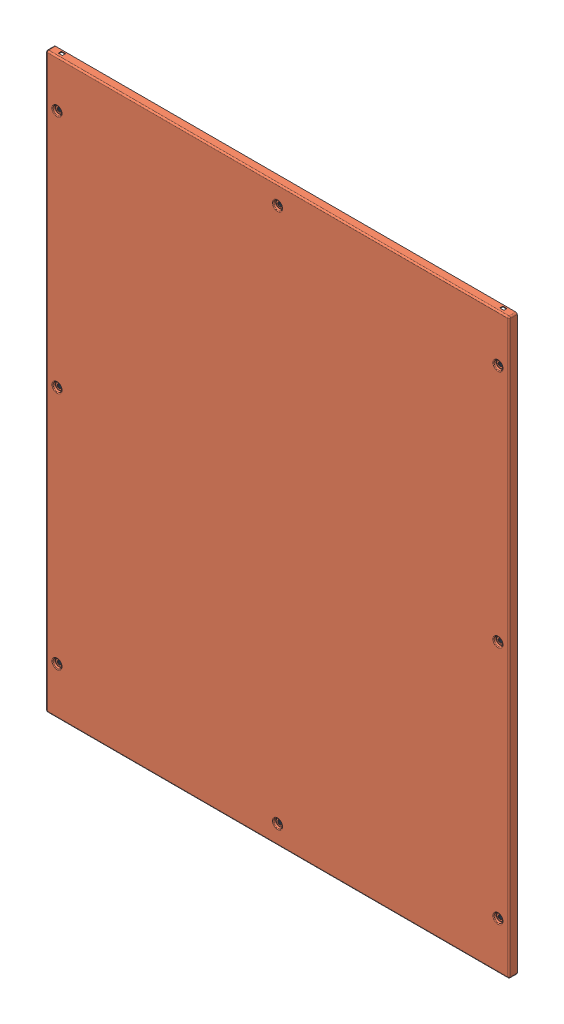
SolidWorks assembly 8176_245, configuration Default. Lengths in mm.
Overall size (968.16 1197.62 31.49).
9 component instances, 2 part files, 27 mates.
Components (placement in the parent):
- 8176_245-side-holder-1: 8176_245-side-holder [Default] at (-483.75 -39.5 -6) x (0 1 0) z (0 0 -1) size (20.59 21 24.87)
- 8176_245-side-holder-2: 8176_245-side-holder [Default] at (-483.75 -1157.5 -6) x (0 -1 0) z (0 0 -1) size (20.59 21 24.87)
- 8176_245-side-holder-3: 8176_245-side-holder [Default] at (-23.25 -1098.5 -6) x (1 0 0) z (0 0 -1) size (20.59 21 24.87)
- 8176_245-side-holder-4: 8176_245-side-holder [Default] at (-944.25 -1098.5 -6) x (-1 0 0) z (0 0 -1) size (20.59 21 24.87)
- 8176_245-side-holder-5: 8176_245-side-holder [Default] at (-23.25 -598.5 -6) x (1 0 0) z (0 0 -1) size (20.59 21 24.87)
- 8176_245-side-holder-6: 8176_245-side-holder [Default] at (-944.25 -598.5 -6) x (-1 0 0) z (0 0 -1) size (20.59 21 24.87)
- 8176_245-side-holder-7: 8176_245-side-holder [Default] at (-23.25 -98.5 -6) x (1 0 0) z (0 0 -1) size (20.59 21 24.87)
- 8176_245-side-holder-8: 8176_245-side-holder [Default] at (-944.25 -98.5 -6) x (-1 0 0) z (0 0 -1) size (20.59 21 24.87)
- 8176_245-side-1: 8176_245-side [Default] at (-483.75 -1197 0) x (-1 0 0) z (0 0 -1) size (968.16 1197.62 24.32)
Mates (geometry in assembly coordinates):
- Deckungsgleich1: coincident anti-aligned: plane of 8176_245-side-holder-3 through (-15.45 1609.6534 -6) normal (0 0 1); plane of 8176_245-side-1 through (-23.25 1612.9885 -6) normal (0 0 -1)
- Konzentrisch1: concentric aligned: cylinder of 8176_245-side-holder-3 through (-23.25 1620.1534 -12) axis (0 0 -1) radius 2.4585; cylinder of 8176_245-side-1 through (-23.25 1620.1534 -6) axis (0 0 -1) radius 4
- Deckungsgleich2: coincident anti-aligned: plane of 8176_245-side-holder-5 through (-15.45 2109.6534 -6) normal (0 0 1); plane of 8176_245-side-1 through (-23.25 2112.9885 -6) normal (0 0 -1)
- Konzentrisch2: concentric aligned: cylinder of 8176_245-side-holder-5 through (-23.25 2120.1534 -12) axis (0 0 -1) radius 2.4585; cylinder of 8176_245-side-1 through (-23.25 2120.1534 -6) axis (0 0 -1) radius 4
- Deckungsgleich3: coincident anti-aligned: plane of 8176_245-side-holder-7 through (-15.45 2609.6534 -6) normal (0 0 1); plane of 8176_245-side-1 through (-23.25 2612.9885 -6) normal (0 0 -1)
- Konzentrisch3: concentric aligned: cylinder of 8176_245-side-holder-7 through (-23.25 2620.1534 -12) axis (0 0 -1) radius 2.4585; cylinder of 8176_245-side-1 through (-23.25 2620.1534 -6) axis (0 0 -1) radius 4
- Deckungsgleich4: coincident anti-aligned: plane of 8176_245-side-holder-1 through (-473.25 2686.9534 -6) normal (0 0 1); plane of 8176_245-side-1 through (-483.75 2671.9885 -6) normal (0 0 -1)
- Konzentrisch4: concentric aligned: cylinder of 8176_245-side-holder-1 through (-483.75 2679.1534 -12) axis (0 0 -1) radius 2.4585; cylinder of 8176_245-side-1 through (-483.75 2679.1534 -6) axis (0 0 -1) radius 4
- Deckungsgleich5: coincident anti-aligned: plane of 8176_245-side-holder-8 through (-952.05 2630.6534 -6) normal (0 0 1); plane of 8176_245-side-1 through (-944.25 2612.9885 -6) normal (0 0 -1)
- Konzentrisch5: concentric aligned: cylinder of 8176_245-side-holder-8 through (-944.25 2620.1534 -12) axis (0 0 -1) radius 2.4585; cylinder of 8176_245-side-1 through (-944.25 2620.1534 -6) axis (0 0 -1) radius 4
- Deckungsgleich6: coincident anti-aligned: plane of 8176_245-side-holder-6 through (-952.05 2130.6534 -6) normal (0 0 1); plane of 8176_245-side-1 through (-944.25 2112.9885 -6) normal (0 0 -1)
- Konzentrisch6: concentric aligned: cylinder of 8176_245-side-holder-6 through (-944.25 2120.1534 -12) axis (0 0 -1) radius 2.4585; cylinder of 8176_245-side-1 through (-944.25 2120.1534 -6) axis (0 0 -1) radius 4
- Deckungsgleich7: coincident anti-aligned: plane of 8176_245-side-holder-4 through (-952.05 1630.6534 -6) normal (0 0 1); plane of 8176_245-side-1 through (-944.25 1612.9885 -6) normal (0 0 -1)
- Konzentrisch7: concentric aligned: cylinder of 8176_245-side-holder-4 through (-944.25 1620.1534 -12) axis (0 0 -1) radius 2.4585; cylinder of 8176_245-side-1 through (-944.25 1620.1534 -6) axis (0 0 -1) radius 4
- Deckungsgleich8: coincident anti-aligned: plane of 8176_245-side-holder-2 through (-494.25 1553.3534 -6) normal (0 0 1); plane of 8176_245-side-1 through (-483.75 1553.9885 -6) normal (0 0 -1)
- Konzentrisch8: concentric aligned: cylinder of 8176_245-side-holder-2 through (-483.75 1561.1534 -12) axis (0 0 -1) radius 2.4585; cylinder of 8176_245-side-1 through (-483.75 1561.1534 -6) axis (0 0 -1) radius 4
- Parallel1: parallel aligned: plane of 8176_245-side-holder-3 through (-15.45 1609.6534 -12.3) normal (1 0 0); plane of 8176_245-side-1 through (0 2715.6534 -3) normal (1 0 0)
- Parallel2: parallel aligned: plane of 8176_245-side-holder-5 through (-15.45 2109.6534 -12.3) normal (1 0 0); plane of 8176_245-side-1 through (0 2715.6534 -3) normal (1 0 0)
- Parallel3: parallel aligned: plane of 8176_245-side-holder-7 through (-15.45 2609.6534 -12.3) normal (1 0 0); plane of 8176_245-side-1 through (0 2715.6534 -3) normal (1 0 0)
- Parallel4: parallel aligned: plane of 8176_245-side-holder-1 through (-473.25 2686.9534 -12.3) normal (0 1 0); plane of 8176_245-side-1 through (-964.5 2718.6534 -3) normal (0 1 0)
- Parallel5: parallel aligned: plane of 8176_245-side-holder-8 through (-952.05 2630.6534 -12.3) normal (-1 0 0); plane of 8176_245-side-1 through (-967.5 2715.6534 -17) normal (-1 0 0)
- Parallel6: parallel aligned: plane of 8176_245-side-holder-6 through (-952.05 2130.6534 -12.3) normal (-1 0 0); plane of 8176_245-side-1 through (-967.5 2715.6534 -17) normal (-1 0 0)
- Parallel7: parallel aligned: plane of 8176_245-side-holder-4 through (-952.05 1630.6534 -12.3) normal (-1 0 0); plane of 8176_245-side-1 through (-967.5 2715.6534 -17) normal (-1 0 0)
- Parallel8: parallel aligned: plane of 8176_245-side-holder-2 through (-494.25 1553.3534 -12.3) normal (0 -1 0); plane of 8176_245-side-1 through (-964.5 1521.6534 -17) normal (0 -1 0)
- Deckungsgleich17: coincident aligned: plane of 8176_245-side-1 through (-964.5 -1194 0) normal (0 0 1); plane of assembly
- Deckungsgleich18: coincident aligned: plane of 8176_245-side-1 through (0 -3 -3) normal (1 0 0); plane of assembly
- Deckungsgleich19: coincident aligned: plane of 8176_245-side-1 through (-964.5 0 -3) normal (0 1 0); plane of assembly
